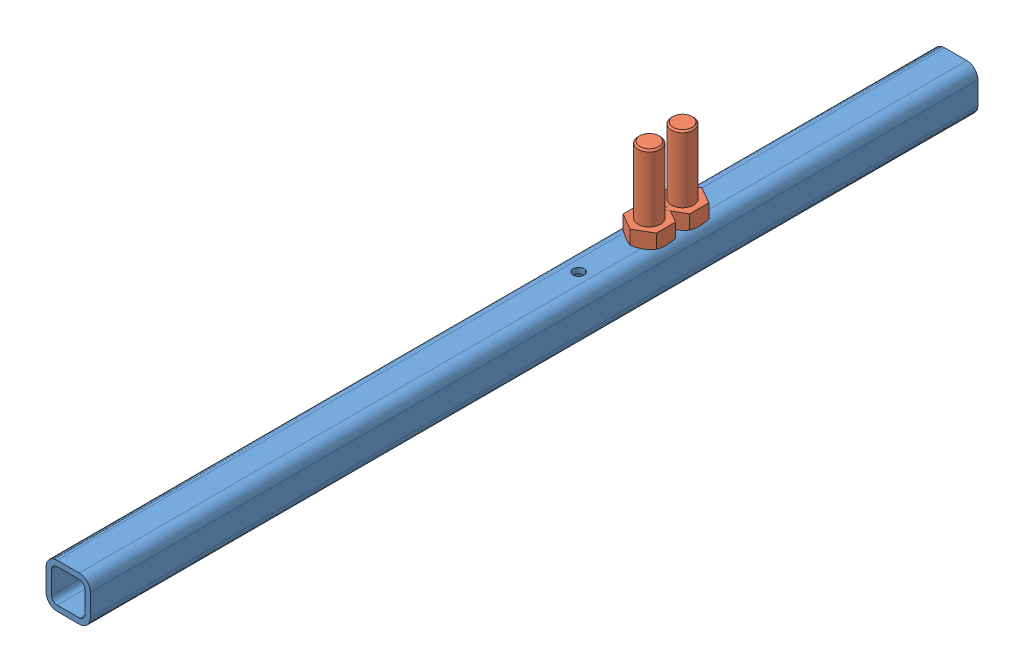
SolidWorks assembly 01-050-00-0, configuration Default. Lengths in mm.
Overall size (50.8 144.78 1016).
3 component instances, 2 part files, 6 mates.
Components (placement in the parent):
- 01-049-00-0-1: 01-049-00-0 [Default] at origin size (50.8 50.8 1016)
- hex bolt_ai_2-2: hex bolt_ai_2 [PreviewCfg] at (30.1625 50.8 -190.5) x (0 1 0) z (-1 0 0) size (93.98 43.99 38.1)
- hex bolt_ai_2-3: hex bolt_ai_2 [PreviewCfg] at (30.1625 50.8 -152.4) x (0 1 0) z (-1 0 0) size (93.98 43.99 38.1)
Mates (geometry in assembly coordinates):
- Coincident1: coincident anti-aligned: plane of 01-049-00-0-1 through (38.1 50.8 508) normal (0 1 0); plane of hex bolt_ai_2-3 through (30.1625 50.8 -72.797) normal (0 -1 0)
- Distance1: distance = 11.1125 mm aligned: plane of hex bolt_ai_2-3 through (11.1125 68.58 -163.3985) normal (-1 0 0); plane of 01-049-00-0-1 through (0 12.7 508) normal (-1 0 0)
- Distance2: distance = 355.6 mm aligned: plane of 01-049-00-0-1 through (38.1 38.1 -508) normal (0 0 -1); moEndPointRef_w of hex bolt_ai_2-3
- Coincident3: coincident anti-aligned: plane of 01-049-00-0-1 through (38.1 50.8 508) normal (0 1 0); plane of hex bolt_ai_2-2 through (30.1625 50.8 -212.497) normal (0 -1 0)
- Distance3: distance = 11.1125 mm aligned: plane of hex bolt_ai_2-2 through (11.1125 68.58 -201.4985) normal (-1 0 0); plane of 01-049-00-0-1 through (0 12.7 508) normal (-1 0 0)
- Distance6: distance = 317.5 mm aligned: plane of 01-049-00-0-1 through (38.1 38.1 -508) normal (0 0 -1); moEndPointRef_w of hex bolt_ai_2-2
